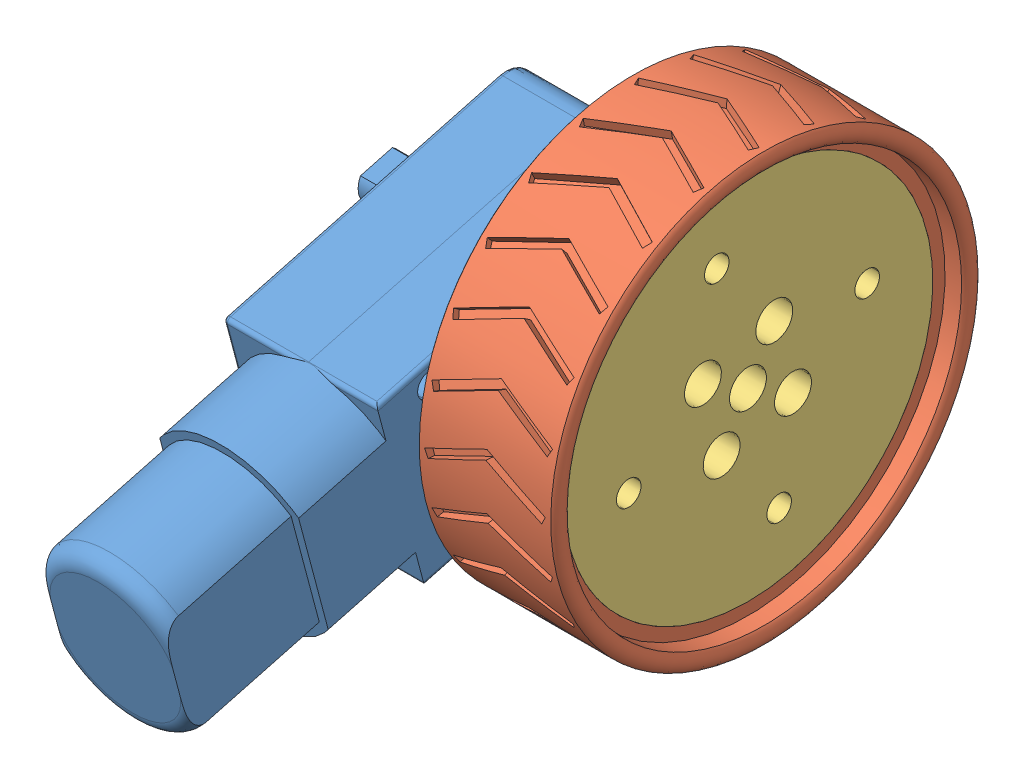
SolidWorks assembly wheel, configuration Default. Lengths in mm.
Overall size (47.16 66.76 87.56).
3 component instances, 3 part files, 4 mates.
Components (placement in the parent):
- dc_motor_with_wheel-1: dc_motor_with_wheel [Défaut] at origin size (37.6 36.38 67.23)
- tyre-1: tyre [Default] at (1.5267 -5.0802 53) x (1 0 0) z (0 0.34528 0.9385) size (16.83 52 52)
- wheel_3wholes_outerlayer-1: wheel_3wholes_outerlayer [Default] at (7.5267 -5.0802 53) x (0 -0.603955 0.797018) z (0 -0.797018 -0.603955) size (45 4 45)
Mates (geometry in assembly coordinates):
- Concentric1: concentric anti-aligned: cylinder of tyre-1 through (-9.7113 -5.0802 53) axis (-1 0 0) radius 22.5; cylinder of wheel_3wholes_outerlayer-1 through (3.5267 -5.0802 53) axis (1 0 0) radius 22.5
- Coincident1: coincident aligned: plane of tyre-1 through (7.5267 17.4438 44.7133) normal (1 0 0); plane of wheel_3wholes_outerlayer-1 through (7.5267 -5.0802 53) normal (1 0 0)
- Concentric2: concentric aligned: cylinder of dc_motor_with_wheel-1 through (0.378 -5.0802 53) axis (-1 0 0) radius 2.7; cylinder of wheel_3wholes_outerlayer-1 through (7.5267 -5.0802 53) axis (-1 0 0) radius 2.25
- Distance1: distance = 16.5487 mm aligned: plane of wheel_3wholes_outerlayer-1 through (7.5267 -5.0802 53) normal (1 0 0); plane of dc_motor_with_wheel-1 through (-9.022 -5.0802 53) normal (1 0 0)
